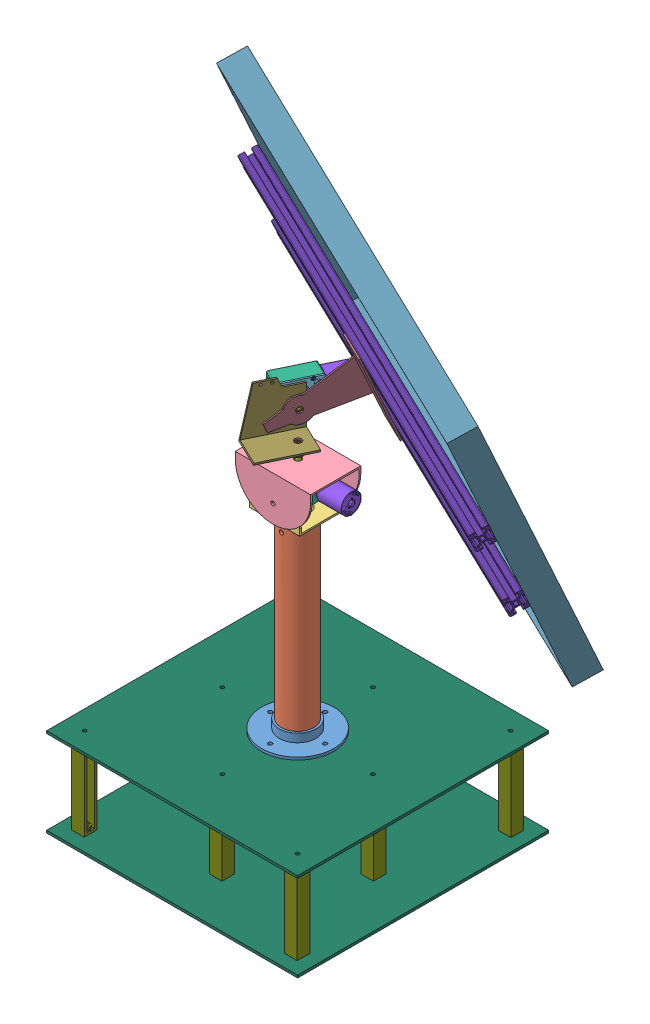
SolidWorks assembly 总装, configuration Default. Lengths in mm.
Overall size (592.52 618.94 417.61).
43 component instances, 17 part files, 41 mates.
Components (placement in the parent):
- 底座-1: 底座 [默认] at origin size (86 13 86)
- 连接柱-1: 连接柱 [默认] at origin size (39 230 39)
- U连接1-1: U连接1 [默认] at (0 200 0) x (0 0 1) z (-1 0 0) size (55 68 60)
- U连接2-1: U连接2 [默认] at (0 276.5165 -0.5) x (0 0 1) z (1 0 0) size (60 53 90)
- Chihai CHW-GW4632-370, DC Worm Gear Motor, 6 V, 6 RPM-1: Chihai CHW-GW4632-370, DC Worm Gear Motor, 6 V, 6 RPM [Default] at (0 275.5 -0.5) size (81.23 43.7 34.06)
  - Cover, Chihai CHW-GW4632-370, DC Worm Gear Motor, 6 V, 6 RPM-1: Cover, Chihai CHW-GW4632-370, DC Worm Gear Motor, 6 V, 6 RPM [Default] at origin size (46 21.6 32)
  - Gear Body, Chihai CHW-GW4632-370, DC Worm Gear Motor, 6 V, 6 RPM-1: Gear Body, Chihai CHW-GW4632-370, DC Worm Gear Motor, 6 V, 6 RPM [Default] at (-1 0 0) size (46 21.1 32)
  - Shaft, Chihai CHW-GW4632-370, DC Worm Gear Motor, 6 V, 6 RPM-1: Shaft, Chihai CHW-GW4632-370, DC Worm Gear Motor, 6 V, 6 RPM [Default] x (0.134746 0 -0.99088) z (0.99088 0 0.134746) size (6 30.5 6)
  - DC Motor, Chihai CHW-GW4632-370, DC Worm Gear Motor, 6 V, 6 RPM-1: DC Motor, Chihai CHW-GW4632-370, DC Worm Gear Motor, 6 V, 6 RPM [Default] at (61 -11.2 -2.5) size (44.2 24 24) (flexible)
    - DC Motor Body, Chihai CHW-GW4632-370, DC Worm Gear Motor, 6 V, 6 RPM-1: DC Motor Body, Chihai CHW-GW4632-370, DC Worm Gear Motor, 6 V, 6 RPM [Default] at origin size (34.2 24 24)
    - DC Motor Shaft, Chihai CHW-GW4632-370, DC Worm Gear Motor, 6 V, 6 RPM-1: DC Motor Shaft, Chihai CHW-GW4632-370, DC Worm Gear Motor, 6 V, 6 RPM [Default] at (-20 0 0) x (1 0 0) z (0 0.450234 0.89291) size (40 2 2)
  - M2 X 6 SS Flat Head Screw, Chihai CHW-GW4632-370, DC Worm Gear Motor, 6 V, 6 RPM-1: M2 X 6 SS Flat Head Screw, Chihai CHW-GW4632-370, DC Worm Gear Motor, 6 V, 6 RPM [default] at (29.4 0.5 14.4) x (-0.837169 0 -0.546944) z (0 1 0) size (3.8 3.8 7.68)
  - M2 X 6 SS Flat Head Screw, Chihai CHW-GW4632-370, DC Worm Gear Motor, 6 V, 6 RPM-2: M2 X 6 SS Flat Head Screw, Chihai CHW-GW4632-370, DC Worm Gear Motor, 6 V, 6 RPM [default] at (-13.4 0.5 14.4) x (-0.837169 0 -0.546944) z (0 1 0) size (3.8 3.8 7.68)
  - M2 X 6 SS Flat Head Screw, Chihai CHW-GW4632-370, DC Worm Gear Motor, 6 V, 6 RPM-3: M2 X 6 SS Flat Head Screw, Chihai CHW-GW4632-370, DC Worm Gear Motor, 6 V, 6 RPM [default] at (-13.4 0.5 -14.4) x (-0.837169 0 -0.546944) z (0 1 0) size (3.8 3.8 7.68)
  - M2 X 6 SS Flat Head Screw, Chihai CHW-GW4632-370, DC Worm Gear Motor, 6 V, 6 RPM-4: M2 X 6 SS Flat Head Screw, Chihai CHW-GW4632-370, DC Worm Gear Motor, 6 V, 6 RPM [default] at (19.6 0.5 -14.4) x (-0.837169 0 -0.546944) z (0 1 0) size (3.8 3.8 7.68)
- 电机联轴-1: 电机联轴 [默认] at (0 298.014 -0.5) x (-0.625484 0 0.780237) z (0.780237 0 0.625484) size (25 12 25)
- L连接1-1: L连接1 [默认] at (-11.2601 298 -20.9074) x (0.90095 0 0.433923) z (-0.433923 0 0.90095) size (38 58 60)
- Chihai CHW-GW4632-370, DC Worm Gear Motor, 6 V, 6 RPM-2: Chihai CHW-GW4632-370, DC Worm Gear Motor, 6 V, 6 RPM [Default] at (-20.071 331 -11.8317) x (0.433923 0 -0.90095) z (0 -1 0) size (81.23 43.7 34.06)
  - Cover, Chihai CHW-GW4632-370, DC Worm Gear Motor, 6 V, 6 RPM-1: Cover, Chihai CHW-GW4632-370, DC Worm Gear Motor, 6 V, 6 RPM [Default] at origin size (46 21.6 32)
  - Gear Body, Chihai CHW-GW4632-370, DC Worm Gear Motor, 6 V, 6 RPM-1: Gear Body, Chihai CHW-GW4632-370, DC Worm Gear Motor, 6 V, 6 RPM [Default] at (-1 0 0) size (46 21.1 32)
  - Shaft, Chihai CHW-GW4632-370, DC Worm Gear Motor, 6 V, 6 RPM-1: Shaft, Chihai CHW-GW4632-370, DC Worm Gear Motor, 6 V, 6 RPM [Default] x (0.134746 0 -0.99088) z (0.99088 0 0.134746) size (6 30.5 6)
  - DC Motor, Chihai CHW-GW4632-370, DC Worm Gear Motor, 6 V, 6 RPM-1: DC Motor, Chihai CHW-GW4632-370, DC Worm Gear Motor, 6 V, 6 RPM [Default] at (61 -11.2 -2.5) size (44.2 24 24) (flexible)
    - DC Motor Body, Chihai CHW-GW4632-370, DC Worm Gear Motor, 6 V, 6 RPM-1: DC Motor Body, Chihai CHW-GW4632-370, DC Worm Gear Motor, 6 V, 6 RPM [Default] at origin size (34.2 24 24)
    - DC Motor Shaft, Chihai CHW-GW4632-370, DC Worm Gear Motor, 6 V, 6 RPM-1: DC Motor Shaft, Chihai CHW-GW4632-370, DC Worm Gear Motor, 6 V, 6 RPM [Default] at (-20 0 0) x (1 0 0) z (0 0.450234 0.89291) size (40 2 2)
  - M2 X 6 SS Flat Head Screw, Chihai CHW-GW4632-370, DC Worm Gear Motor, 6 V, 6 RPM-1: M2 X 6 SS Flat Head Screw, Chihai CHW-GW4632-370, DC Worm Gear Motor, 6 V, 6 RPM [default] at (29.4 0.5 14.4) x (-0.837169 0 -0.546944) z (0 1 0) size (3.8 3.8 7.68)
  - M2 X 6 SS Flat Head Screw, Chihai CHW-GW4632-370, DC Worm Gear Motor, 6 V, 6 RPM-2: M2 X 6 SS Flat Head Screw, Chihai CHW-GW4632-370, DC Worm Gear Motor, 6 V, 6 RPM [default] at (-13.4 0.5 14.4) x (-0.837169 0 -0.546944) z (0 1 0) size (3.8 3.8 7.68)
  - M2 X 6 SS Flat Head Screw, Chihai CHW-GW4632-370, DC Worm Gear Motor, 6 V, 6 RPM-3: M2 X 6 SS Flat Head Screw, Chihai CHW-GW4632-370, DC Worm Gear Motor, 6 V, 6 RPM [default] at (-13.4 0.5 -14.4) x (-0.837169 0 -0.546944) z (0 1 0) size (3.8 3.8 7.68)
  - M2 X 6 SS Flat Head Screw, Chihai CHW-GW4632-370, DC Worm Gear Motor, 6 V, 6 RPM-4: M2 X 6 SS Flat Head Screw, Chihai CHW-GW4632-370, DC Worm Gear Motor, 6 V, 6 RPM [default] at (19.6 0.5 -14.4) x (-0.837169 0 -0.546944) z (0 1 0) size (3.8 3.8 7.68)
- L连接2-1: L连接2 [默认] at (17.8418 401.3074 -38.697) x (0.162287 -0.927429 -0.336955) z (-0.90095 0 -0.433923) size (100 97 42)
- 电机联轴-2: 电机联轴 [默认] at (-1.5889 331 -2.9302) x (-0.429064 -0.149225 0.890862) z (0.064752 -0.988803 -0.134444) size (25 12 25)
- Solar PV Panel-1: Solar PV Panel [Default] at (52.0238 362.4159 -63.5776) x (0.162287 -0.927429 -0.336955) z (0.402433 0.373999 -0.835567) size (300 590 30.5)
- 底座亚克力板1-1: 底座亚克力板1 [默认] at (-150 -3 150) size (300 3 300)
- 底座亚克力板1-2: 底座亚克力板1 [默认] at (-150 -106 150) size (300 3 300)
- 底座支柱2-5: 底座支柱2 [默认] at (135.2552 -103 -119.7792) x (0 1 0) z (0 0 1) size (100 15 15)
- 底座支柱2-6: 底座支柱2 [默认] at (119.7792 -103 135.2552) x (0 1 0) z (-1 0 0) size (100 15 15)
- 底座支柱2-7: 底座支柱2 [默认] at (-135.2552 -103 119.7792) x (0 1 0) z (0 0 -1) size (100 15 15)
- 底座支柱2-8: 底座支柱2 [默认] at (-119.7792 -103 -135.2552) x (0 1 0) z (1 0 0) size (100 15 15)
- 底座支柱2-9: 底座支柱2 [默认] at (97.9759 -103 7.5) x (0 1 0) z (0 0 1) size (100 15 15)
- 底座支柱2-10: 底座支柱2 [默认] at (-7.5 -103 97.9759) x (0 1 0) z (-1 0 0) size (100 15 15)
- 底座支柱2-11: 底座支柱2 [默认] at (-97.9759 -103 -7.5) x (0 1 0) z (0 0 -1) size (100 15 15)
- 底座支柱2-12: 底座支柱2 [默认] at (7.5 -103 -97.9759) x (0 1 0) z (1 0 0) size (100 15 15)
- 铝型材2020R1.5_p1-1: 铝型材2020R1.5_p1 [默认<按加工>] at (-211.2894 321.5788 -196.7073) x (0.90095 0 0.433923) z (-0.402433 -0.373999 0.835567) size (590 20 20)
- 铝型材2020R1.5_p1-2: 铝型材2020R1.5_p1 [默认<按加工>] at (-224.2723 395.7731 -169.751) x (0.90095 0 0.433923) z (-0.402433 -0.373999 0.835567) size (590 20 20)
Mates (geometry in assembly coordinates):
- 同心1: concentric aligned: cylinder of 底座-1 through (0 13 0) axis (0 -1 0) radius 19; cylinder of 连接柱-1 through (0 230 0) axis (0 -1 0) radius 19.5
- 重合1: coincident aligned: plane of 底座-1 through (0 0 0) normal (0 -1 0); plane of 连接柱-1 through (0 0 0) normal (0 -1 0)
- 同心2: concentric aligned: cylinder of 连接柱-1 through (0 230 0) axis (0 -1 0) radius 16.5; cylinder of U连接1-1 through (0 230 0) axis (0 -1 0) radius 16.5
- 同心3: concentric aligned: cylinder of 连接柱-1 through (0 215 -19.5) axis (0 0 1) radius 2.5; cylinder of U连接1-1 through (0 215 -27.5) axis (0 0 1) radius 2.5
- 重合3: coincident anti-aligned: plane of U连接1-1 through (30 230 27.5) normal (0 0 1); plane of U连接2-1 through (-45 228.5 27.5) normal (0 0 -1)
- 同心4: concentric anti-aligned: cylinder of U连接1-1 through (0 250 -27.5) axis (0 0 1) radius 2.5; cylinder of U连接2-1 through (0 250 29.5) axis (0 0 -1) radius 2.5
- 平行1: parallel anti-aligned: plane of U连接1-1 through (30 232 -25.5) normal (0 1 0); plane of U连接2-1 through (-45 279.5 -28.5) normal (0 -1 0)
- 同心5: concentric aligned: circle of U连接2-1; cylinder of Chihai CHW-GW4632-370, DC Worm Gear Motor, 6 V, 6 RPM-1/Shaft, Chihai CHW-GW4632-370, DC Worm Gear Motor, 6 V, 6 RPM-1 through (0 296 -0.5) axis (0 1 0) radius 1.25
- 重合5: coincident anti-aligned: plane of U连接2-1 through (-45 279.5 -28.5) normal (0 -1 0); plane of Chihai CHW-GW4632-370, DC Worm Gear Motor, 6 V, 6 RPM-1/Cover, Chihai CHW-GW4632-370, DC Worm Gear Motor, 6 V, 6 RPM-1 through (-9 279.5 8.5) normal (0 1 0)
- 平行2: parallel anti-aligned: plane of U连接2-1 through (-45 228.5 -28.5) normal (0 0 1); plane of Chihai CHW-GW4632-370, DC Worm Gear Motor, 6 V, 6 RPM-1/Gear Body, Chihai CHW-GW4632-370, DC Worm Gear Motor, 6 V, 6 RPM-1 through (-15 254.9 -16.5) normal (0 0 -1)
- 同心6: concentric aligned: cylinder of Chihai CHW-GW4632-370, DC Worm Gear Motor, 6 V, 6 RPM-1/Shaft, Chihai CHW-GW4632-370, DC Worm Gear Motor, 6 V, 6 RPM-1 through (0 265.5 -0.5) axis (0 1 0) radius 3; cylinder of 电机联轴-1 through (0 298.014 -0.5) axis (0 1 0) radius 2.5
- 重合6: coincident anti-aligned: plane of Chihai CHW-GW4632-370, DC Worm Gear Motor, 6 V, 6 RPM-1/Shaft, Chihai CHW-GW4632-370, DC Worm Gear Motor, 6 V, 6 RPM-1 through (0 296 -0.5) normal (0 1 0); plane of 电机联轴-1 through (7.8186 296 -10.253) normal (0 -1 0)
- 同心7: concentric anti-aligned: cylinder of 电机联轴-1 through (0 298.014 -0.5) axis (0 1 0) radius 2.5; cylinder of L连接1-1 through (0 348 -0.5) axis (0 -1 0) radius 4
- 重合7: coincident anti-aligned: plane of 电机联轴-1 through (1.5637 298 -2.4506) normal (0 1 0); plane of L连接1-1 through (-37.2955 298 33.1496) normal (0 -1 0)
- 重合8: coincident aligned: plane of 连接柱-1 through (0 0 0) normal (0 0 1)
- 同心8: concentric anti-aligned: cylinder of L连接1-1 through (17.7689 331 6.3931) axis (-0.90095 0 -0.433923) radius 3.5; cylinder of Chihai CHW-GW4632-370, DC Worm Gear Motor, 6 V, 6 RPM-2/Shaft, Chihai CHW-GW4632-370, DC Worm Gear Motor, 6 V, 6 RPM-1 through (-29.0805 331 -16.1709) axis (0.90095 0 0.433923) radius 3
- 重合9: coincident anti-aligned: plane of L连接1-1 through (-37.2955 356 33.1496) normal (-0.90095 0 -0.433923); plane of Chihai CHW-GW4632-370, DC Worm Gear Motor, 6 V, 6 RPM-2/Cover, Chihai CHW-GW4632-370, DC Worm Gear Motor, 6 V, 6 RPM-1 through (-6.053 340 -31.7188) normal (0.90095 0 0.433923)
- 平行3: parallel aligned: plane of U连接2-1 through (-45 281.5 29.5) normal (0 1 0); plane of Chihai CHW-GW4632-370, DC Worm Gear Motor, 6 V, 6 RPM-2/Gear Body, Chihai CHW-GW4632-370, DC Worm Gear Motor, 6 V, 6 RPM-1 through (-45.1394 347 -7.2562) normal (0 1 0)
- 重合11: coincident aligned: plane of Chihai CHW-GW4632-370, DC Worm Gear Motor, 6 V, 6 RPM-2/Shaft, Chihai CHW-GW4632-370, DC Worm Gear Motor, 6 V, 6 RPM-1 through (-1.6015 331 -2.9362) normal (0.90095 0 0.433923); plane of 电机联轴-2 through (-0.5288 331.3731 -5.1634) normal (0.90095 0 0.433923)
- 同心9: concentric aligned: cylinder of Chihai CHW-GW4632-370, DC Worm Gear Motor, 6 V, 6 RPM-2/Shaft, Chihai CHW-GW4632-370, DC Worm Gear Motor, 6 V, 6 RPM-1 through (-1.6015 331 -2.9362) axis (0.90095 0 0.433923) radius 1.25; cylinder of 电机联轴-2 through (-1.5889 331 -2.9302) axis (0.90095 0 0.433923) radius 2.5
- 同心10: concentric anti-aligned: cylinder of Chihai CHW-GW4632-370, DC Worm Gear Motor, 6 V, 6 RPM-2/Shaft, Chihai CHW-GW4632-370, DC Worm Gear Motor, 6 V, 6 RPM-1 through (-1.6015 331 -2.9362) axis (0.90095 0 0.433923) radius 1.25; cylinder of L连接2-1 through (0.2004 331 -2.0684) axis (-0.90095 0 -0.433923) radius 3.5
- 重合12: coincident anti-aligned: plane of L连接2-1 through (-1.6015 331 -2.9362) normal (-0.90095 0 -0.433923); plane of 电机联轴-2 through (-0.5288 331.3731 -5.1634) normal (0.90095 0 0.433923)
- 重合14: coincident anti-aligned: plane of 底座-1 through (0 0 0) normal (0 -1 0); plane of 底座亚克力板1-1 through (-150 0 150) normal (0 1 0)
- 同心11: concentric aligned: cylinder of 连接柱-1 through (0 230 0) axis (0 -1 0) radius 16.5; cylinder of 底座亚克力板1-1 through (0 0 0) axis (0 -1 0) radius 12.5
- 平行4: parallel aligned: plane of 底座亚克力板1-1 through (-150 0 150) normal (0 0 1)
- 重合18: coincident aligned: plane of 底座亚克力板1-1 through (150 0 150) normal (1 0 0); plane of 底座亚克力板1-2 through (150 -103 150) normal (1 0 0)
- 重合19: coincident aligned: plane of 底座亚克力板1-1 through (-150 0 -150) normal (0 0 -1); plane of 底座亚克力板1-2 through (-150 -103 -150) normal (0 0 -1)
- 重合20: coincident anti-aligned: plane of 底座亚克力板1-1 through (-150 -3 150) normal (0 -1 0); plane of 底座支柱2-5 through (120.2552 -3 -119.7792) normal (0 1 0)
- 同心12: concentric aligned: cylinder of 底座亚克力板1-1 through (127.2792 0 -127.2792) axis (0 -1 0) radius 2.15; cylinder of 底座支柱2-5 through (127.2792 -3 -127.2792) axis (0 -1 0) radius 2.15
- 重合21: coincident anti-aligned: plane of 底座亚克力板1-2 through (-150 -103 150) normal (0 1 0); plane of 底座支柱2-5 through (120.2552 -103 -119.7792) normal (0 -1 0)
- 重合22: coincident anti-aligned: plane of 底座亚克力板1-1 through (-150 -3 150) normal (0 -1 0); plane of 底座支柱2-9 through (82.9759 -3 7.5) normal (0 1 0)
- 同心13: concentric aligned: cylinder of 底座亚克力板1-1 through (90 0 0) axis (0 -1 0) radius 2.15; cylinder of 底座支柱2-9 through (90 -3 0) axis (0 -1 0) radius 2.15
- 重合23: coincident aligned: plane of Solar PV Panel-1 through (-177.3405 234.5216 -267.195) normal (-0.90095 0 -0.433923); plane of 铝型材2020R1.5_p1-1 through (-216.0895 326.2829 -186.7409) normal (-0.90095 0 -0.433923)
- 重合24: coincident anti-aligned: plane of L连接2-1 through (17.8418 401.3074 -38.697) normal (0.402433 0.373999 -0.835567); plane of 铝型材2020R1.5_p1-1 through (317.6263 309.9556 64.7987) normal (-0.402433 -0.373999 0.835567)
- 重合25: coincident anti-aligned: plane of Solar PV Panel-1 through (52.0238 362.4159 -63.5776) normal (-0.402433 -0.373999 0.835567); plane of 铝型材2020R1.5_p1-1 through (322.916 333.2019 53.8156) normal (0.402433 0.373999 -0.835567)
- 重合26: coincident aligned: plane of L连接2-1 through (33.2656 307.8165 -70.7213) normal (0.162287 -0.927429 -0.336955); plane of 铝型材2020R1.5_p1-1 through (323.3428 313.6509 52.9296) normal (0.162287 -0.927429 -0.336955)
- 重合27: coincident aligned: plane of Solar PV Panel-1 through (-177.3405 234.5216 -267.195) normal (-0.90095 0 -0.433923); plane of 铝型材2020R1.5_p1-2 through (-229.0724 400.4773 -159.7845) normal (-0.90095 0 -0.433923)
- 重合28: coincident anti-aligned: plane of L连接2-1 through (17.8418 401.3074 -38.697) normal (0.402433 0.373999 -0.835567); plane of 铝型材2020R1.5_p1-2 through (304.6433 384.15 91.7551) normal (-0.402433 -0.373999 0.835567)
- 重合29: coincident aligned: plane of L连接2-1 through (17.0369 400.5594 -37.0258) normal (-0.162287 0.927429 0.336955); plane of 铝型材2020R1.5_p1-2 through (309.086 408.2264 82.5307) normal (-0.162287 0.927429 0.336955)
- 宽度1: width anti-aligned: plane of L连接2-1 through (17.0369 400.5594 -37.0258) normal (-0.90095 0 -0.433923); plane of Solar PV Panel-1 through (53.0749 400.5594 -19.6689) normal (0.90095 0 0.433923); plane of L连接2-1 through (354.22 234.5216 -11.1805) normal (0.90095 0 0.433923); plane of Solar PV Panel-1 through (-177.3405 234.5216 -267.195) normal (-0.90095 0 -0.433923)
- 宽度2: width aligned: plane of Solar PV Panel-1 through (-226.0265 512.7503 -166.1086) normal (-0.162287 0.927429 0.336955); plane of 铝型材2020R1.5_p1-2 through (-177.3405 234.5216 -267.195) normal (0.162287 -0.927429 -0.336955); plane of Solar PV Panel-1 through (309.086 408.2264 82.5307) normal (-0.162287 0.927429 0.336955); plane of 铝型材2020R1.5_p1-1 through (323.3428 313.6509 52.9296) normal (0.162287 -0.927429 -0.336955)
